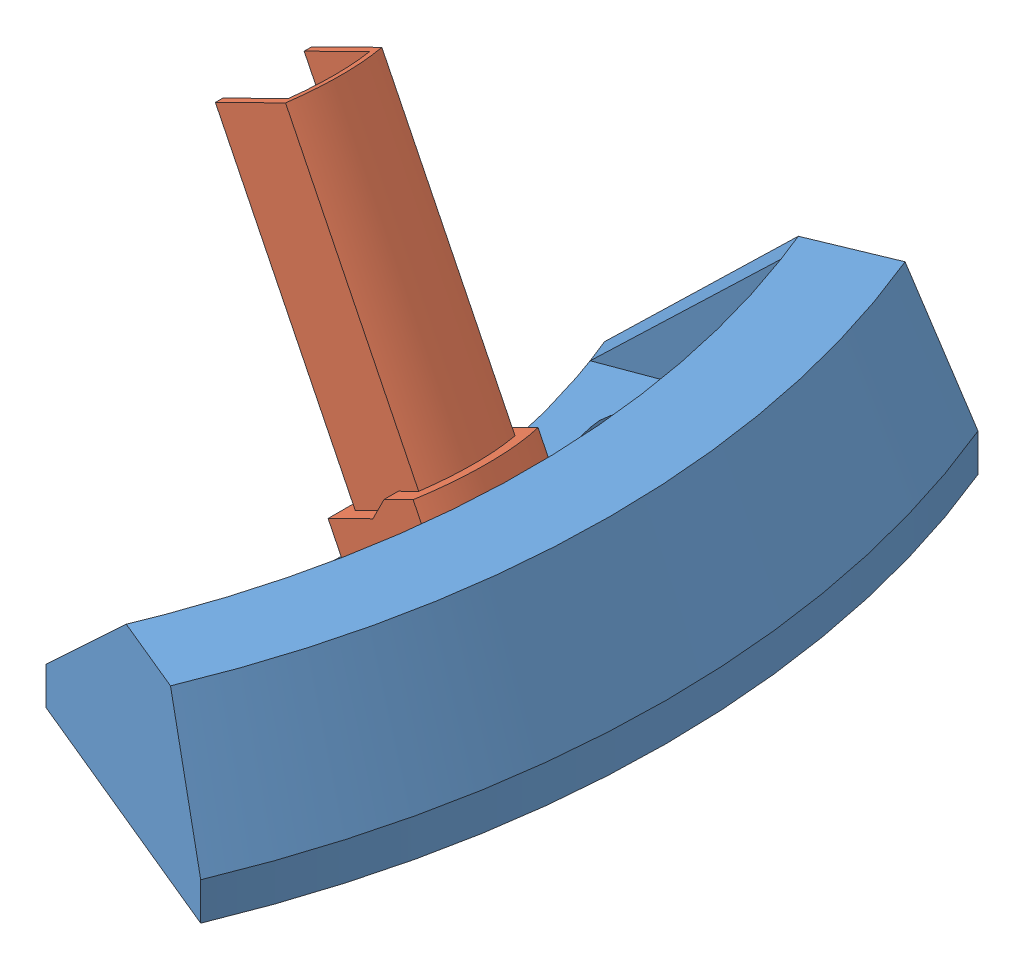
SolidWorks assembly leg-assembly, configuration Default. Lengths in mm.
Overall size (51.18 60.25 103.32).
2 component instances, 2 part files, 1 mates.
Components (placement in the parent):
- attachment-1-1: attachment-1 [Default] at (-75.537 38.5795 82.3143) size (45.38 22.48 103.32)
- stand-leg-1: stand-leg [Default] at (48.1141 45.9214 78.1283) x (0.896749 0.442539 0) z (0 0 1) size (15.3 59 16.6)
Mates (geometry in assembly coordinates):
- Tangent1: tangent anti-aligned: plane of attachment-1-1 through (14.0793 43.5795 45.194) normal (0 1 0); cylinder of stand-leg-1 through (41.446 62.1193 94.7283) axis (0 0 -1) radius 18.5398
